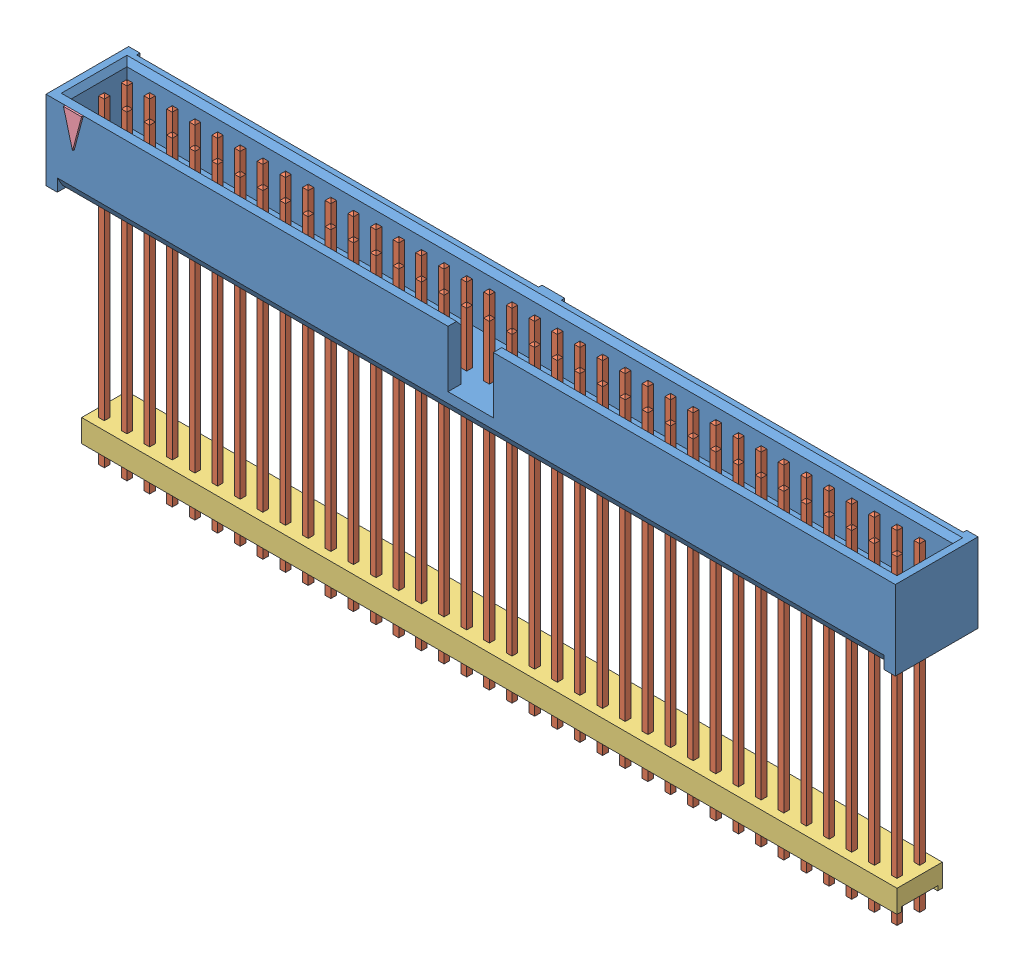
SolidWorks assembly ZSS_136_09_G_D_1340, configuration Default. Lengths in mm.
Overall size (95.25 36.32 9.47).
4 component instances, 4 part files, 0 mates.
Components (placement in the parent):
- _ZSS_136_09_G_D_1340_socket_2-1: _ZSS_136_09_G_D_1340_socket_2 [Default] at origin size (95.25 9.27 9.27)
- _ZSS_136_09_G_D_1340_pins_4-1: _ZSS_136_09_G_D_1340_pins_4 [Default] at origin size (93.98 36.32 8)
- _ZSS_136_09_G_D_1340_bsocket_6-1: _ZSS_136_09_G_D_1340_bsocket_6 [Default] at (0 -25.146 0) size (91.44 2.54 5.08)
- _ZSS_136__D_indicator_8-1: _ZSS_136__D_indicator_8 [Default] at (-44.45 8.89 4.6355) size (2.03 3.81 0.2)
